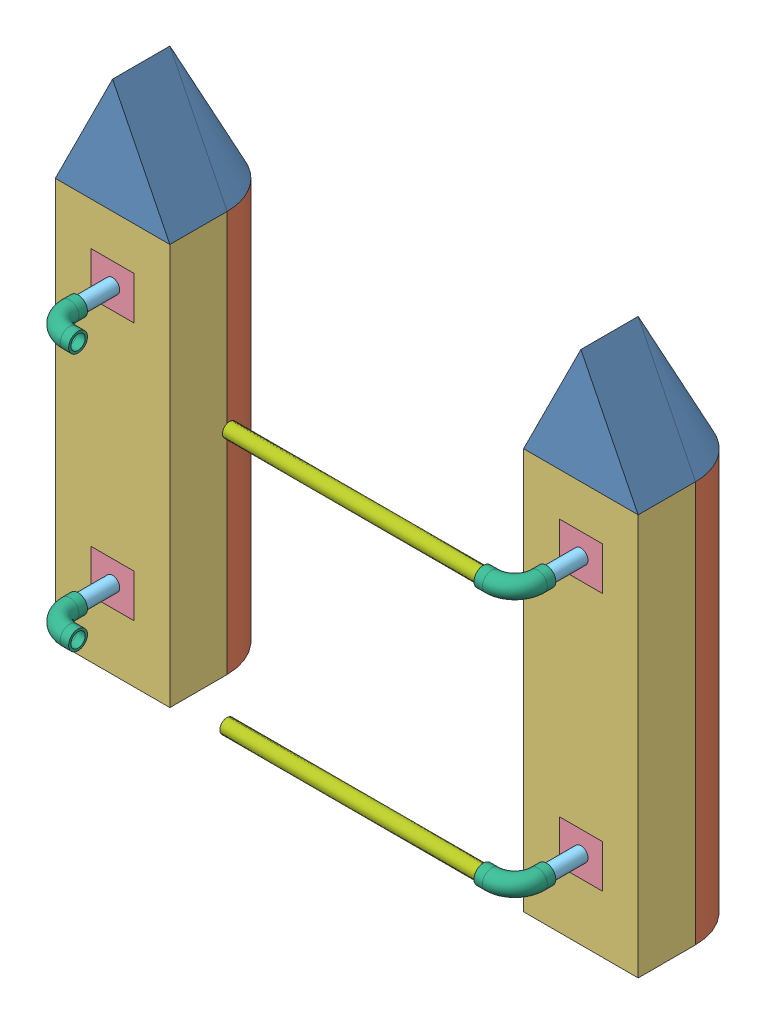
SolidWorks assembly Assem2, configuration Default. Lengths in mm.
Overall size (1033.6 914.4 337.12).
20 component instances, 7 part files, 39 mates.
Components (placement in the parent):
- HALF CONE-1: HALF CONE [Default] at (-666.2492 31.9523 191.3433) size (203.2 203.2 203.2)
- HALF CONE-2: HALF CONE [Default] at (164.1468 31.9523 191.3433) size (203.2 203.2 203.2)
- HALF CYLINDER-1: HALF CYLINDER [Default] at (-666.2492 -34.7227 191.3433) x (1 0 0) z (0 -1 0) size (203.2 101.6 711.2)
- HALF CYLINDER-2: HALF CYLINDER [Default] at (164.1468 -34.7227 191.3433) x (1 0 0) z (0 -1 0) size (203.2 101.6 711.2)
- RECTANGULER-1: RECTANGULER [Default] at (265.7468 -745.9227 191.3433) x (-1 0 0) z (0 1 0) size (203.2 101.6 711.2)
- RECTANGULER-2: RECTANGULER [Default] at (-564.6492 -745.9227 191.3433) x (-1 0 0) z (0 1 0) size (203.2 101.6 711.2)
- timber box-1: timber box [Default] at (164.1468 -149.0227 216.7433) size (76.2 76.2 76.2)
- timber box-2: timber box [Default] at (164.1468 -606.2227 216.7433) size (76.2 76.2 76.2)
- timber box-3: timber box [Default] at (-666.2492 -606.2227 216.7433) size (76.2 76.2 76.2)
- timber box-4: timber box [Default] at (-666.2492 -149.0227 216.7433) size (76.2 76.2 76.2)
- pvc pipe 4-1: pvc pipe 4 [Default] at (-666.2492 -149.0227 267.5433) x (-0.896206 -0.443638 0) z (0 0 1) size (25.4 25.4 101.6)
- pvc pipe 4-2: pvc pipe 4 [Default] at (164.1468 -606.2227 267.5433) x (0.241616 0.970372 0) z (0 0 1) size (25.4 25.4 101.6)
- pvc pipe 4-3: pvc pipe 4 [Default] at (164.1468 -149.0227 267.5433) size (25.4 25.4 101.6)
- pvc pipe 4-4: pvc pipe 4 [Default] at (-666.2492 -606.2227 267.5433) size (25.4 25.4 101.6)
- l bow-1: l bow [Default] at (-625.3779 -149.0227 369.1433) x (0 0 -1) z (0 1 0) size (72.57 72.57 33.4)
- l bow-2: l bow [Default] at (-625.3779 -606.2227 369.1433) x (0 0 -1) z (0 1 0) size (72.57 72.57 33.4)
- l bow-3: l bow [Default] at (123.2755 -149.0227 369.1433) x (0 0 -1) z (0 -1 0) size (72.57 72.57 33.4)
- l bow-4: l bow [Default] at (123.2755 -606.2227 369.1433) x (0 0 -1) z (0 -1 0) size (72.57 72.57 33.4)
- pvc pipe 18.5-1: pvc pipe 18.5 [Default] at (-346.4437 -606.2227 410.0147) x (0 0.908382 -0.418141) z (1 0 0) size (25.4 25.4 469.9)
- pvc pipe 18.5-2: pvc pipe 18.5 [Default] at (-341.7188 -149.0227 410.0147) x (0 0.399718 -0.916638) z (1 0 0) size (25.4 25.4 469.9)
Mates (geometry in assembly coordinates):
- Coincident3: coincident aligned: line of HALF CONE-1 through (-767.8492 -34.7227 292.9433) axis (1 0 0); line of HALF CONE-2 through (62.5468 -34.7227 292.9433) axis (1 0 0)
- Parallel2: parallel aligned: plane of HALF CONE-1 through (-564.6492 -34.7227 191.3433) normal (0 -1 0); plane of HALF CONE-2 through (265.7468 -34.7227 191.3433) normal (0 -1 0)
- Coincident6: coincident anti-aligned: plane of HALF CONE-2 through (265.7468 -34.7227 191.3433) normal (0 -1 0); plane of HALF CYLINDER-2 through (164.1468 -34.7227 191.3433) normal (0 1 0)
- Concentric1: concentric anti-aligned: circle of HALF CONE-2; circle of HALF CYLINDER-2
- Parallel3: parallel anti-aligned: line of HALF CONE-2 through (62.5468 -34.7227 292.9433) axis (1 0 0); line of HALF CYLINDER-2 through (265.7468 -745.9227 191.3433) axis (-1 0 0)
- Coincident11: coincident anti-aligned: circle of HALF CONE-1; circle of HALF CYLINDER-1
- Parallel5: parallel anti-aligned: line of HALF CONE-1 through (-767.8492 -34.7227 292.9433) axis (1 0 0); line of HALF CYLINDER-1 through (-564.6492 -745.9227 191.3433) axis (-1 0 0)
- Coincident14: coincident anti-aligned: plane of HALF CONE-1 through (-564.6492 -34.7227 191.3433) normal (0 -1 0); plane of RECTANGULER-2 through (-564.6492 -34.7227 191.3433) normal (0 1 0)
- Coincident15: coincident anti-aligned: plane of HALF CYLINDER-1 through (-767.8492 -745.9227 191.3433) normal (0 0 1); plane of RECTANGULER-2 through (-564.6492 -34.7227 191.3433) normal (0 0 -1)
- Coincident16: coincident anti-aligned: line of HALF CYLINDER-1 through (-767.8492 -745.9227 191.3433) axis (0 1 0); line of RECTANGULER-2 through (-767.8492 -34.7227 191.3433) axis (0 -1 0)
- Coincident17: coincident anti-aligned: plane of HALF CONE-2 through (265.7468 -34.7227 191.3433) normal (0 -1 0); plane of RECTANGULER-1 through (265.7468 -34.7227 191.3433) normal (0 1 0)
- Coincident18: coincident anti-aligned: plane of HALF CYLINDER-2 through (62.5468 -745.9227 191.3433) normal (0 0 1); plane of RECTANGULER-1 through (265.7468 -34.7227 191.3433) normal (0 0 -1)
- Coincident19: coincident: line of HALF CYLINDER-2 through (62.5468 -745.9227 191.3433) axis (0 1 0); plane of RECTANGULER-1 through (62.5468 -34.7227 191.3433) normal (-1 0 0)
- Coincident34: coincident aligned: plane of timber box-3 through (-628.1492 -644.3227 292.9433) normal (1 0 0); plane of timber box-4 through (-628.1492 -187.1227 292.9433) normal (1 0 0)
- Coincident35: coincident anti-aligned: plane of RECTANGULER-2 through (-628.1492 -110.9227 216.7433) normal (0 -1 0); plane of timber box-4 through (-704.3492 -110.9227 292.9433) normal (0 1 0)
- Coincident36: coincident anti-aligned: plane of RECTANGULER-2 through (-628.1492 -644.3227 216.7433) normal (0 1 0); plane of timber box-3 through (-704.3492 -644.3227 292.9433) normal (0 -1 0)
- Coincident37: coincident aligned: line of RECTANGULER-2 through (-628.1492 -644.3227 292.9433) axis (0 1 0); line of timber box-3 through (-628.1492 -644.3227 292.9433) axis (0 1 0)
- Coincident38: coincident aligned: line of RECTANGULER-2 through (-628.1492 -110.9227 292.9433) axis (-1 0 0); line of timber box-4 through (-628.1492 -110.9227 292.9433) axis (-1 0 0)
- Coincident39: coincident aligned: plane of timber box-1 through (202.2468 -187.1227 292.9433) normal (1 0 0); plane of timber box-2 through (202.2468 -644.3227 292.9433) normal (1 0 0)
- Coincident40: coincident anti-aligned: plane of RECTANGULER-1 through (202.2468 -110.9227 216.7433) normal (0 -1 0); plane of timber box-1 through (126.0468 -110.9227 292.9433) normal (0 1 0)
- Coincident41: coincident anti-aligned: plane of RECTANGULER-1 through (202.2468 -644.3227 216.7433) normal (0 1 0); plane of timber box-2 through (126.0468 -644.3227 292.9433) normal (0 -1 0)
- Coincident42: coincident aligned: line of RECTANGULER-1 through (202.2468 -644.3227 292.9433) axis (0 1 0); line of timber box-2 through (202.2468 -644.3227 292.9433) axis (0 1 0)
- Coincident43: coincident aligned: line of RECTANGULER-1 through (202.2468 -187.1227 292.9433) axis (0 1 0); line of timber box-1 through (202.2468 -187.1227 292.9433) axis (0 1 0)
- Coincident44: coincident aligned: line of RECTANGULER-1 through (202.2468 -568.1227 292.9433) axis (-1 0 0); line of timber box-2 through (202.2468 -568.1227 292.9433) axis (-1 0 0)
- Coincident46: coincident aligned: circle of timber box-3; circle of pvc pipe 4-4
- Concentric2: concentric aligned: circle of timber box-1; circle of pvc pipe 4-3
- Parallel6: parallel aligned: plane of pvc pipe 4-2 through (164.1468 -606.2227 369.1433) normal (0 0 1); plane of pvc pipe 4-4 through (-666.2492 -606.2227 369.1433) normal (0 0 1)
- Coincident49: coincident aligned: circle of timber box-1; circle of pvc pipe 4-3
- Coincident51: coincident aligned: circle of timber box-4; circle of pvc pipe 4-1
- Coincident52: coincident aligned: circle of timber box-2; circle of pvc pipe 4-2
- Coincident53: coincident aligned: circle of pvc pipe 4-2; circle of l bow-4
- Concentric3: concentric anti-aligned: circle of pvc pipe 4-3; circle of l bow-3
- Coincident54: coincident aligned: circle of pvc pipe 4-3; circle of l bow-3
- Coincident55: coincident aligned: circle of pvc pipe 4-1; circle of l bow-1
- Coincident56: coincident aligned: circle of pvc pipe 4-4; circle of l bow-2
- Concentric4: concentric anti-aligned: circle of l bow-2; circle of l bow-4
- Concentric5: concentric anti-aligned: circle of l bow-1; circle of l bow-3
- Concentric6: concentric anti-aligned: circle of l bow-1; circle of pvc pipe 18.5-2
- Concentric7: concentric anti-aligned: circle of pvc pipe 18.5-1; circle of l bow-2
